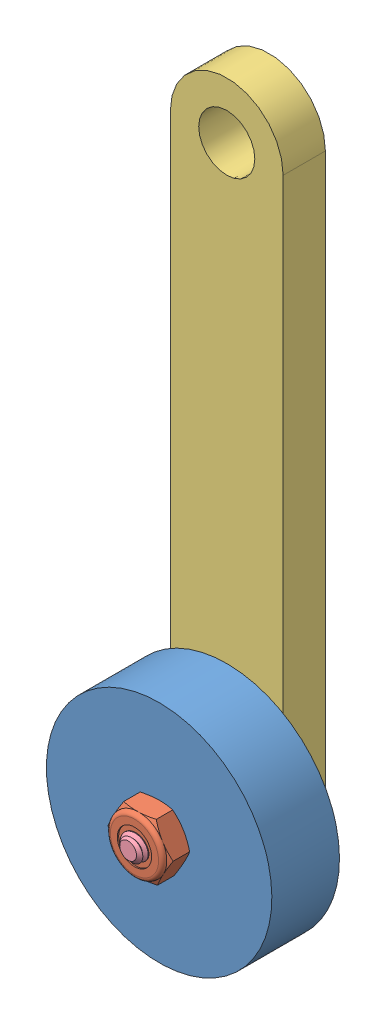
SolidWorks assembly bottom_link_assy, configuration Default. Lengths in mm.
Overall size (31.92 85.81 16.21).
4 component instances, 4 part files, 11 mates.
Components (placement in the parent):
- Mass_blank-1: Mass_blank [Default] at (0 -63.5 4.7625) x (0.9527 0.303914 0) z (0 0 1) size (25.4 25.4 7.62)
- 4_40_THIN_LOCKNUT_90633A005-1: 4_40_THIN_LOCKNUT_90633A005 [90633A005] at (0 -63.5 12.3825) x (0.853828 0.520556 0) z (0.520556 -0.853828 0) size (6.35 2.86 7.33)
- bottom_link-1: bottom_link [Default] at (0 0 4.7625) x (0 1 0) z (-1 0 0) size (76.2 4.76 12.7)
- 4_40-625-countersunk-91253A112-1: 4_40-625-countersunk-91253A112 [91253A112] at (0 -63.5 0) x (-0.923728 -0.383049 0) z (0 0 -1) size (6.48 6.48 16.21)
Mates (geometry in assembly coordinates):
- Coincident40: coincident anti-aligned: plane of Mass_blank-1 through (0 -63.5 12.3825) normal (0 0 1); plane of 4_40_THIN_LOCKNUT_90633A005-1 through (-5.5736 -60.4573 12.3825) normal (0 0 -1)
- Concentric30: concentric aligned: cylinder of Mass_blank-1 through (0 -63.5 12.3825) axis (0 0 -1) radius 12.7; cylinder of 4_40_THIN_LOCKNUT_90633A005-1 through (0 -63.5 16.4306) axis (0 0 -1) radius 1.9297
- Concentric31: concentric anti-aligned: cylinder of Mass_blank-1 through (0 -63.5 12.3825) axis (0 0 1) radius 1.632; cylinder of bottom_link-1 through (0 -63.5 0) axis (0 0 -1) radius 1.632
- Coincident41: coincident anti-aligned: plane of bottom_link-1 through (0 0 4.7625) normal (0 0 1); plane of Mass_blank-1 through (0 -63.5 4.7625) normal (0 0 -1)
- Coincident42: coincident anti-aligned: plane of bottom_link-1 through (0 0 0) normal (0 0 -1); plane of ? through (1.8032 -65.5164 0) normal (0 0 1)
- Concentric32: concentric aligned: cylinder of bottom_link-1 through (0 -63.5 0) axis (0 0 -1) radius 1.632; cylinder of ? through (0 -63.5 -1.4986) axis (0 0 -1) radius 2.7051
- Symmetric1: symmetric aligned: plane of bottom_link-1 through (-6.35 0 0) normal (-1 0 0); plane of bottom_link-1 through (6.35 0 0) normal (1 0 0); plane of assembly through (0 0 0) normal (1 0 0)
- Coincident43: coincident anti-aligned: plane of bottom_link-1 through (0 0 0) normal (0 0 -1); plane of assembly through (0 0 0) normal (0 0 1)
- Coincident44: coincident: line of bottom_link-1 through (-6.35 0 0) axis (0 0 1); plane of assembly
- Concentric33: concentric aligned: cylinder of bottom_link-1 through (0 -63.5 0) axis (0 0 -1) radius 1.632; cylinder of 4_40-625-countersunk-91253A112-1 through (0 -63.5 0) axis (0 0 -1) radius 3.2385
- Coincident45: coincident aligned: plane of bottom_link-1 through (0 0 0) normal (0 0 -1); plane of 4_40-625-countersunk-91253A112-1 through (0.5448 -64.8139 0) normal (0 0 -1)
